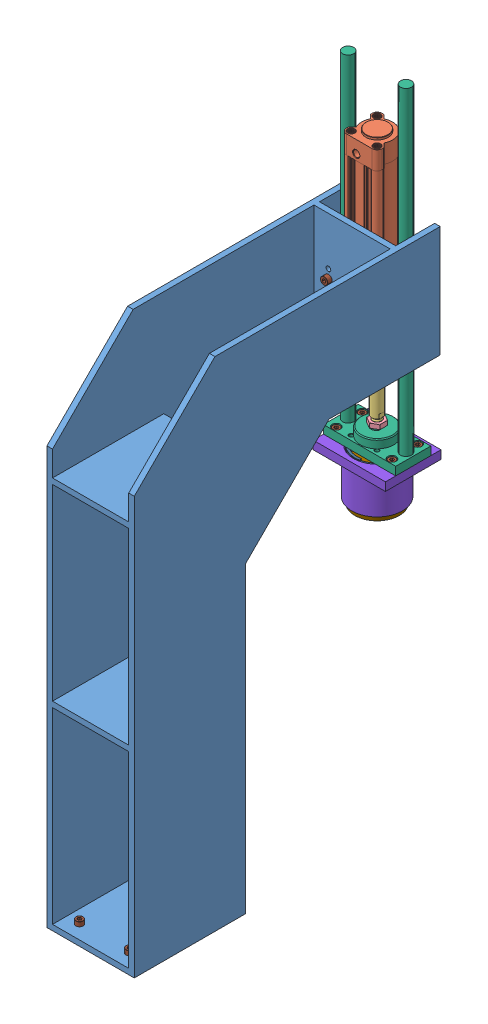
SolidWorks assembly Montagem prensa, configuration Default. Lengths in mm.
Overall size (157 1141.2 565).
31 component instances, 14 part files, 43 mates.
Components (placement in the parent):
- Suporte prensa-1: Suporte prensa [Default] at (129.4691 60.9907 640.0637) size (157 895 550)
- Prensa com suporte especial-1: Prensa com suporte especial [Default] at (60.9691 826.9907 125.0637) x (1 0 0) z (0 -1 0) size (137 70 588)
  - 1463770_DSBC_50_150_PPSA__Z_0_-1: 1463770_DSBC_50_150_PPSA__Z_0_ [Default] at origin size (64 64 286.8)
  - 1463770_DSBC_50_150__K_-1: 1463770_DSBC_50_150__K_ [Default] at (0 0 150) size (50 50 290.8)
  - DIN_439_B___M16x1_5_F_-1: DIN_439_B___M16x1_5_F_ [Default] at (0 0 199.8) x (1 0 0) z (0 -1 0) size (24 8 27.71)
  - 150292 FENG-50-400-KF---(asm_0)-1: 150292 FENG-50-400-KF---(asm_0) [Default] at origin size (137 70 588) (flexible)
    - 150292 FENG-50-KF---(GK)-1: 150292 FENG-50-KF---(GK) [Default] at origin size (137 70 150)
    - 150292 FENG-50-400-KF---(JS)-1: 150292 FENG-50-400-KF---(JS) [Default] at (0 0 143.8) size (130 63 588)
    - DIN-912 - M8x40(F)-1: DIN-912 - M8x40(F) [Default] at (23.25 23.25 26) x (1 0 0) z (0 -1 0) size (13 48.35 13)
    - DIN-912 - M8x40(F)-2: DIN-912 - M8x40(F) [Default] at (-23.25 23.25 26) x (1 0 0) z (0 -1 0) size (13 48.35 13)
    - DIN-912 - M8x40(F)-3: DIN-912 - M8x40(F) [Default] at (23.25 -23.25 26) x (1 0 0) z (0 -1 0) size (13 48.35 13)
    - DIN-912 - M8x40(F)-4: DIN-912 - M8x40(F) [Default] at (-23.25 -23.25 26) x (1 0 0) z (0 -1 0) size (13 48.35 13)
- Ponta_prensa-1: Ponta_prensa [Default] at (60.9691 594.1907 125.0637) x (-1 0 0) z (0 0 1) size (130 80 100)
- pino_prensa-1: pino_prensa [Default] at (60.9691 569.1907 125.0637) x (0 -1 0) z (-0.04225 0 0.999107) size (65 85 85)
- mola_presa-1: mola_presa [Default] at (60.9691 569.1907 125.0637) x (0.980196 0 -0.198031) z (0.198031 0 0.980196) size (82.37 29.25 81.45)
- socket head cap screw_iso-2: socket head cap screw_iso [ISO 4762 M8 x 25 - 25N] at (18.4691 854.6907 178.0637) x (0 0 -1) z (1 0 0) size (33 13 13)
- socket head cap screw_iso-3: socket head cap screw_iso [ISO 4762 M8 x 25 - 25N] at (103.4691 854.6907 178.0637) x (0 0 -1) z (1 0 0) size (33 13 13)
- socket head cap screw_iso-4: socket head cap screw_iso [ISO 4762 M8 x 25 - 25N] at (103.4691 808.1907 178.0637) x (0 0 -1) z (0.172554 -0.985 0) size (33 13 13)
- socket head cap screw_iso-5: socket head cap screw_iso [ISO 4762 M8 x 25 - 25N] at (18.4691 808.1907 178.0637) x (0 0 -1) z (1 0 0) size (33 13 13)
- socket head cap screw_iso-7: socket head cap screw_iso [ISO 4762 M8 x 30 - 30N] at (15.9691 78.9907 465.0637) x (0 -1 0) z (0 0 1) size (38 13 13)
- socket head cap screw_iso-8: socket head cap screw_iso [ISO 4762 M8 x 30 - 30N] at (105.9691 78.9907 465.0637) x (0 -1 0) z (0 0 1) size (38 13 13)
- socket head cap screw_iso-9: socket head cap screw_iso [ISO 4762 M8 x 30 - 30N] at (105.9691 78.9907 615.0637) x (0 -1 0) z (0 0 1) size (38 13 13)
- socket head cap screw_iso-10: socket head cap screw_iso [ISO 4762 M8 x 30 - 30N] at (15.9691 78.9907 615.0637) x (0 -1 0) z (0 0 1) size (38 13 13)
- socket head cap screw_iso-12: socket head cap screw_iso [ISO 4762 M8 x 20 - 20N] at (10.9691 608.1907 101.8137) x (0 -1 0) z (0 0 1) size (28 13 13)
- socket head cap screw_iso-13: socket head cap screw_iso [ISO 4762 M8 x 20 - 20N] at (10.9691 608.1907 148.3137) x (0 -1 0) z (0 0 1) size (28 13 13)
- socket head cap screw_iso-14: socket head cap screw_iso [ISO 4762 M8 x 20 - 20N] at (110.9691 608.1907 101.8137) x (0 -1 0) z (0 0 1) size (28 13 13)
- socket head cap screw_iso-15: socket head cap screw_iso [ISO 4762 M8 x 20 - 20N] at (110.9691 608.1907 148.3137) x (0 -1 0) z (0 0 1) size (28 13 13)
- mola_prensa_suporte-1: mola_prensa_suporte [Default] at (18.4691 869.6907 150.0636) x (-0.035626 -0.999365 0) z (0.999365 -0.035626 0) size (8.14 7.52 8.15)
- mola_prensa_suporte-2: mola_prensa_suporte [Default] at (103.4691 793.1907 150.0636) x (1 0 0) z (0 1 0) size (8.14 7.52 8.15)
- pino_prensa_suporte-1: pino_prensa_suporte [Default] at (18.4691 869.6907 150.0637) x (0 0 1) z (-1 0 0) size (12.5 9 9)
- pino_prensa_suporte2-1: pino_prensa_suporte2 [Default] at (103.4691 793.1907 150.0637) x (0 0 1) z (-0.743294 0.668965 0) size (12.5 9 9)
Mates (geometry in assembly coordinates):
- Coincident1: coincident anti-aligned: plane of Suporte prensa-1 through (129.4691 60.9907 160.0637) normal (0 0 -1); plane of Prensa com suporte especial-1/150292 FENG-50-400-KF---(asm_0)-1/150292 FENG-50-KF---(GK)-1 through (94.9691 826.9907 160.0637) normal (0 0 1)
- Coincident2: coincident anti-aligned: plane of Suporte prensa-1 through (129.4691 -505.8153 90.0637) normal (-1 0 0); plane of Prensa com suporte especial-1/150292 FENG-50-400-KF---(asm_0)-1/150292 FENG-50-KF---(GK)-1 through (129.4691 755.9907 160.0637) normal (1 0 0)
- Coincident3: coincident anti-aligned: plane of Prensa com suporte especial-1/150292 FENG-50-400-KF---(asm_0)-1/150292 FENG-50-400-KF---(JS)-1 through (60.9691 594.1907 125.0637) normal (0 -1 0); plane of Ponta_prensa-1 through (60.9691 594.1907 125.0637) normal (0 1 0)
- Concentric2: concentric anti-aligned: cylinder of Ponta_prensa-1 through (10.9691 579.1907 101.8137) axis (0 -1 0) radius 3.4; cylinder of Prensa com suporte especial-1/150292 FENG-50-400-KF---(asm_0)-1/150292 FENG-50-400-KF---(JS)-1 through (10.9691 609.1907 101.8137) axis (0 1 0) radius 4.5
- Concentric3: concentric anti-aligned: cylinder of Prensa com suporte especial-1/150292 FENG-50-400-KF---(asm_0)-1/150292 FENG-50-400-KF---(JS)-1 through (110.9691 609.1907 101.8137) axis (0 1 0) radius 4.5; cylinder of Ponta_prensa-1 through (110.9691 579.1907 101.8137) axis (0 -1 0) radius 3.4
- Concentric4: concentric anti-aligned: cylinder of Ponta_prensa-1 through (60.9691 594.1907 125.0637) axis (0 -1 0) radius 41; cylinder of pino_prensa-1 through (60.9691 569.1907 125.0637) axis (0 1 0) radius 41
- Coincident4: coincident anti-aligned: plane of Ponta_prensa-1 through (60.9691 559.1907 125.0637) normal (0 1 0); plane of pino_prensa-1 through (101.9325 559.1907 126.796) normal (0 -1 0)
- Concentric5: concentric aligned: cylinder of Ponta_prensa-1 through (60.9691 514.1907 125.0637) axis (0 1 0) radius 45.5; circle of mola_presa-1
- Coincident5: coincident anti-aligned: plane of pino_prensa-1 through (103.4312 569.1907 126.8593) normal (0 1 0); plane of mola_presa-1 through (60.9691 569.1907 125.0637) normal (0 -1 0)
- Concentric6: concentric aligned: cylinder of Suporte prensa-1 through (18.4691 869.6907 90.0627) axis (0 0 1) radius 4.25; cylinder of Prensa com suporte especial-1/150292 FENG-50-400-KF---(asm_0)-1/150292 FENG-50-KF---(GK)-1 through (18.4691 869.6907 142.5637) axis (0 0 1) radius 4.5
- Concentric7: concentric aligned: cylinder of Suporte prensa-1 through (18.4691 854.6907 90.0627) axis (0 0 1) radius 4.5; cylinder of socket head cap screw_iso-2 through (18.4691 854.6907 209.8137) axis (0 0 1) radius 6.5
- Coincident6: coincident anti-aligned: plane of Suporte prensa-1 through (129.4691 60.9907 170.0637) normal (0 0 1); plane of socket head cap screw_iso-2 through (18.4691 861.1907 170.0637) normal (0 0 -1)
- Concentric8: concentric aligned: cylinder of Suporte prensa-1 through (103.4691 854.6907 90.0627) axis (0 0 1) radius 4.5; cylinder of socket head cap screw_iso-3 through (103.4691 854.6907 209.8137) axis (0 0 1) radius 6.5
- Coincident7: coincident anti-aligned: plane of Suporte prensa-1 through (129.4691 60.9907 170.0637) normal (0 0 1); plane of socket head cap screw_iso-3 through (103.4691 861.1907 170.0637) normal (0 0 -1)
- Concentric9: concentric aligned: cylinder of Suporte prensa-1 through (103.4691 808.1907 90.0627) axis (0 0 1) radius 4.5; cylinder of socket head cap screw_iso-4 through (103.4691 808.1907 209.8137) axis (0 0 1) radius 6.5
- Coincident8: coincident anti-aligned: plane of Suporte prensa-1 through (129.4691 60.9907 170.0637) normal (0 0 1); plane of socket head cap screw_iso-4 through (109.8716 809.3123 170.0637) normal (0 0 -1)
- Concentric10: concentric aligned: cylinder of Suporte prensa-1 through (18.4691 808.1907 90.0627) axis (0 0 1) radius 4.5; cylinder of socket head cap screw_iso-5 through (18.4691 808.1907 209.8137) axis (0 0 1) radius 6.5
- Coincident9: coincident anti-aligned: plane of Suporte prensa-1 through (129.4691 60.9907 170.0637) normal (0 0 1); plane of socket head cap screw_iso-5 through (18.4691 814.6907 170.0637) normal (0 0 -1)
- Concentric11: concentric aligned: cylinder of Suporte prensa-1 through (15.9691 60.9897 465.0637) axis (0 1 0) radius 4.5; cylinder of socket head cap screw_iso-7 through (15.9691 110.7407 465.0637) axis (0 1 0) radius 6.5
- Coincident10: coincident anti-aligned: plane of Suporte prensa-1 through (-17.5309 70.9907 640.0637) normal (0 1 0); plane of socket head cap screw_iso-7 through (22.4691 70.9907 465.0637) normal (0 -1 0)
- Concentric12: concentric aligned: cylinder of Suporte prensa-1 through (105.9691 60.9897 465.0637) axis (0 1 0) radius 4.5; cylinder of socket head cap screw_iso-8 through (105.9691 110.7407 465.0637) axis (0 1 0) radius 6.5
- Coincident11: coincident anti-aligned: plane of Suporte prensa-1 through (-17.5309 70.9907 640.0637) normal (0 1 0); plane of socket head cap screw_iso-8 through (112.4691 70.9907 465.0637) normal (0 -1 0)
- Concentric13: concentric aligned: cylinder of Suporte prensa-1 through (105.9691 60.9897 615.0637) axis (0 1 0) radius 4.5; cylinder of socket head cap screw_iso-9 through (105.9691 110.7407 615.0637) axis (0 1 0) radius 6.5
- Coincident12: coincident anti-aligned: plane of Suporte prensa-1 through (-17.5309 70.9907 640.0637) normal (0 1 0); plane of socket head cap screw_iso-9 through (112.4691 70.9907 615.0637) normal (0 -1 0)
- Concentric14: concentric aligned: cylinder of Suporte prensa-1 through (15.9691 60.9897 615.0637) axis (0 1 0) radius 4.5; cylinder of socket head cap screw_iso-10 through (15.9691 110.7407 615.0637) axis (0 1 0) radius 6.5
- Coincident13: coincident anti-aligned: plane of Suporte prensa-1 through (-17.5309 70.9907 640.0637) normal (0 1 0); plane of socket head cap screw_iso-10 through (22.4691 70.9907 615.0637) normal (0 -1 0)
- Concentric15: concentric aligned: cylinder of Prensa com suporte especial-1/150292 FENG-50-400-KF---(asm_0)-1/150292 FENG-50-400-KF---(JS)-1 through (10.9691 609.1907 101.8137) axis (0 1 0) radius 7.5; cylinder of socket head cap screw_iso-12 through (10.9691 639.9407 101.8137) axis (0 1 0) radius 6.5
- Coincident14: coincident anti-aligned: plane of Prensa com suporte especial-1/150292 FENG-50-400-KF---(asm_0)-1/150292 FENG-50-400-KF---(JS)-1 through (10.9691 600.1907 106.3137) normal (0 1 0); plane of socket head cap screw_iso-12 through (17.4691 600.1907 101.8137) normal (0 -1 0)
- Concentric16: concentric aligned: cylinder of Prensa com suporte especial-1/150292 FENG-50-400-KF---(asm_0)-1/150292 FENG-50-400-KF---(JS)-1 through (10.9691 609.1907 148.3137) axis (0 1 0) radius 4.5; cylinder of socket head cap screw_iso-13 through (10.9691 639.9407 148.3137) axis (0 1 0) radius 6.5
- Coincident15: coincident anti-aligned: plane of Prensa com suporte especial-1/150292 FENG-50-400-KF---(asm_0)-1/150292 FENG-50-400-KF---(JS)-1 through (10.9691 600.1907 152.8137) normal (0 1 0); plane of socket head cap screw_iso-13 through (17.4691 600.1907 148.3137) normal (0 -1 0)
- Concentric17: concentric aligned: cylinder of Prensa com suporte especial-1/150292 FENG-50-400-KF---(asm_0)-1/150292 FENG-50-400-KF---(JS)-1 through (110.9691 609.1907 101.8137) axis (0 1 0) radius 7.5; cylinder of socket head cap screw_iso-14 through (110.9691 639.9407 101.8137) axis (0 1 0) radius 6.5
- Coincident16: coincident anti-aligned: plane of Prensa com suporte especial-1/150292 FENG-50-400-KF---(asm_0)-1/150292 FENG-50-400-KF---(JS)-1 through (110.9691 600.1907 106.3137) normal (0 1 0); plane of socket head cap screw_iso-14 through (117.4691 600.1907 101.8137) normal (0 -1 0)
- Concentric18: concentric aligned: cylinder of Prensa com suporte especial-1/150292 FENG-50-400-KF---(asm_0)-1/150292 FENG-50-400-KF---(JS)-1 through (110.9691 609.1907 148.3137) axis (0 1 0) radius 7.5; cylinder of socket head cap screw_iso-15 through (110.9691 639.9407 148.3137) axis (0 1 0) radius 6.5
- Coincident17: coincident anti-aligned: plane of Prensa com suporte especial-1/150292 FENG-50-400-KF---(asm_0)-1/150292 FENG-50-400-KF---(JS)-1 through (110.9691 600.1907 152.8137) normal (0 1 0); plane of socket head cap screw_iso-15 through (117.4691 600.1907 148.3137) normal (0 -1 0)
- Concentric19: concentric anti-aligned: cylinder of Prensa com suporte especial-1/150292 FENG-50-400-KF---(asm_0)-1/150292 FENG-50-KF---(GK)-1 through (18.4691 869.6907 142.5637) axis (0 0 1) radius 4.5; circle of mola_prensa_suporte-1
- Coincident18: coincident: point of Prensa com suporte especial-1/150292 FENG-50-400-KF---(asm_0)-1/150292 FENG-50-KF---(GK)-1; moEndPointRef_w of mola_prensa_suporte-1
- Concentric20: concentric anti-aligned: cylinder of Prensa com suporte especial-1/150292 FENG-50-400-KF---(asm_0)-1/150292 FENG-50-KF---(GK)-1 through (103.4691 793.1907 142.5637) axis (0 0 1) radius 4.5; circle of mola_prensa_suporte-2
- Coincident19: coincident: plane of Prensa com suporte especial-1/150292 FENG-50-400-KF---(asm_0)-1/150292 FENG-50-KF---(GK)-1 through (103.4691 793.1907 142.5637) normal (0 0 1); unknown of mola_prensa_suporte-2
- Concentric21: concentric anti-aligned: cylinder of Prensa com suporte especial-1/150292 FENG-50-400-KF---(asm_0)-1/150292 FENG-50-KF---(GK)-1 through (18.4691 869.6907 142.5637) axis (0 0 1) radius 4.5; cylinder of pino_prensa_suporte-1 through (18.4691 869.6907 150.0637) axis (0 0 -1) radius 4.5
- Concentric22: concentric anti-aligned: cylinder of Prensa com suporte especial-1/150292 FENG-50-400-KF---(asm_0)-1/150292 FENG-50-KF---(GK)-1 through (103.4691 793.1907 142.5637) axis (0 0 1) radius 4.5; cylinder of pino_prensa_suporte2-1 through (103.4691 793.1907 150.0637) axis (0 0 -1) radius 4.5
- Coincident20: coincident anti-aligned: plane of Prensa com suporte especial-1/150292 FENG-50-400-KF---(asm_0)-1/150292 FENG-50-KF---(GK)-1 through (94.9691 826.9907 160.0637) normal (0 0 1); circle of pino_prensa_suporte-1
- Coincident21: coincident aligned: plane of Prensa com suporte especial-1/150292 FENG-50-400-KF---(asm_0)-1/150292 FENG-50-KF---(GK)-1 through (94.9691 826.9907 160.0637) normal (0 0 1); circle of pino_prensa_suporte2-1
- Perpendicular1: perpendicular: plane of pino_prensa_suporte2-1 through (99.2859 791.5323 160.0637) normal (-0.743294 0.668965 0)
